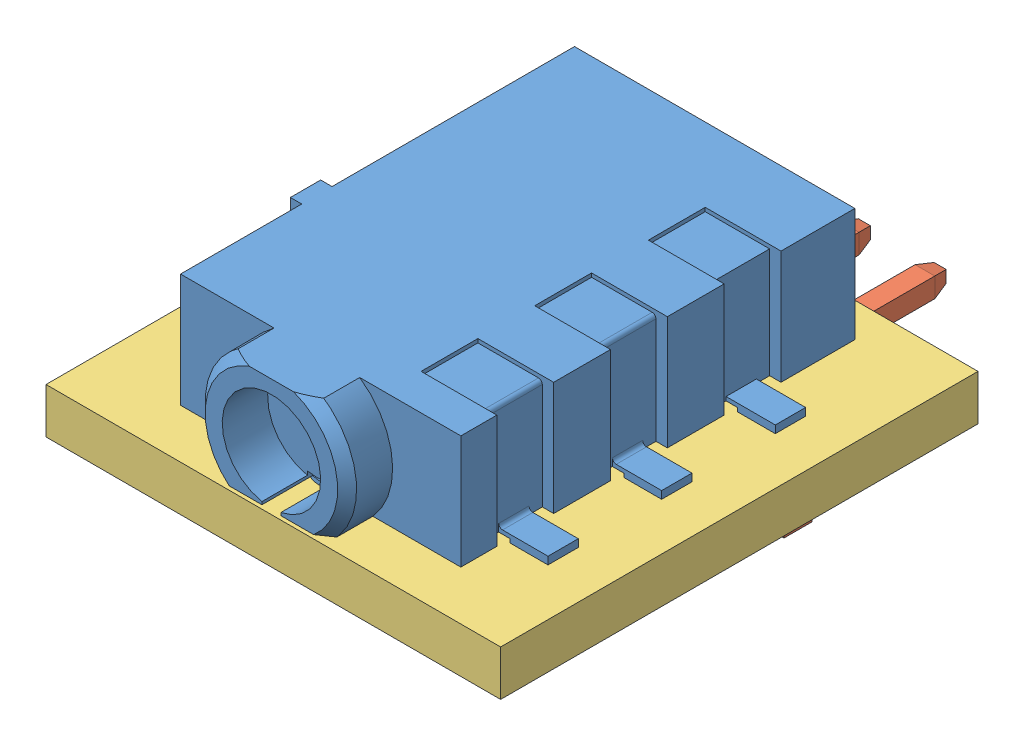
SolidWorks assembly TH1, configuration ﾃﾞﾌｫﾙﾄ. Lengths in mm.
Overall size (12 8.35 16.6).
4 component instances, 3 part files, 0 mates.
Components (placement in the parent):
- CUI_SJ1-2535-SMT-1: CUI_SJ1-2535-SMT [ﾃﾞﾌｫﾙﾄ] at (31.4501 41.6501 11.4) x (-1 0 0) z (0 0 -1) size (9.4 3.5 11.6)
- 10112690-G03-02ULFc-1: 10112690-G03-02ULFc [ﾃﾞﾌｫﾙﾄ] at (33.5001 34.9499 0.75) x (0 1 0) z (0 0 -1) size (4.05 4 11.75)
- 689264912-1: 689264912 [ﾃﾞﾌｫﾙﾄ] at (31.5 39.6 0) size (12 1.2 12.6)
  - Extruded_35-1: Extruded_35 [ﾃﾞﾌｫﾙﾄ] at origin size (12 1.2 12.6)
